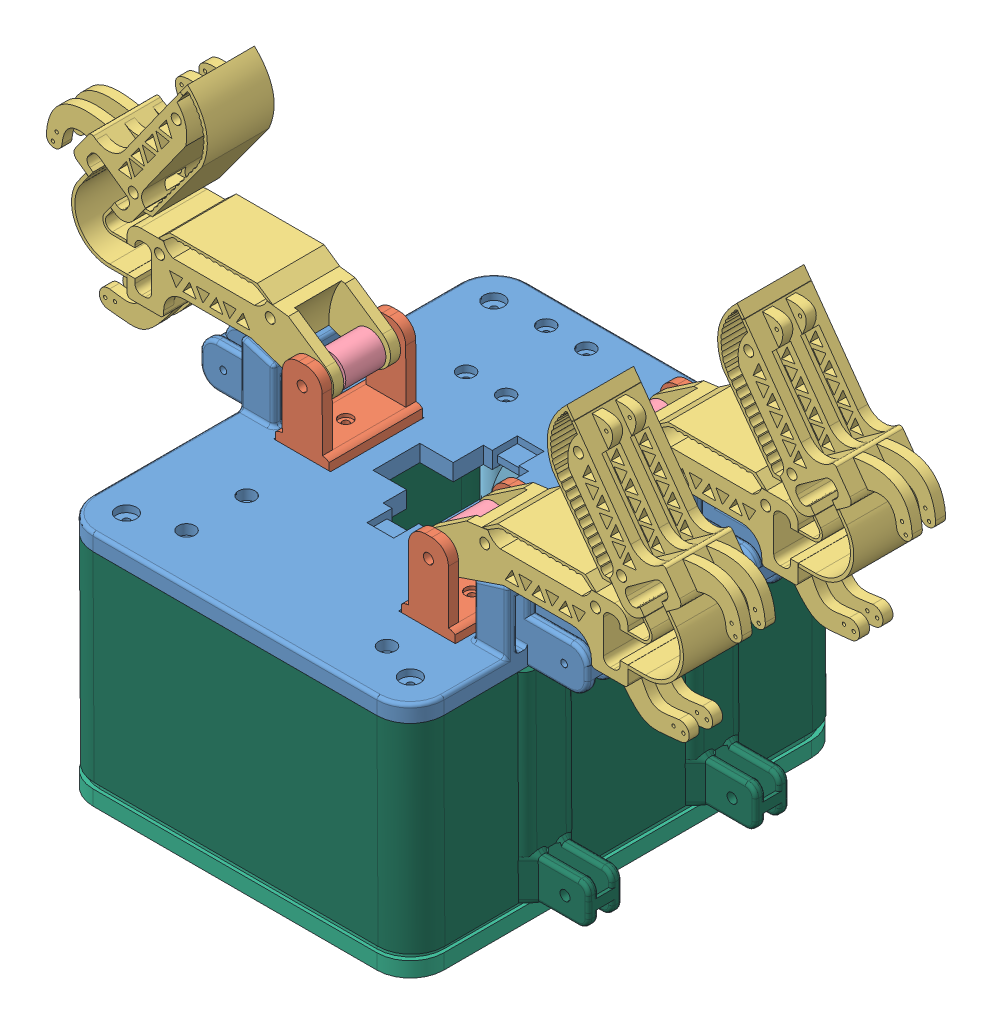
SolidWorks assembly aerial_grasping_robot_hand, configuration 默认. Lengths in mm.
Overall size (234.65 146.24 130.32).
24 component instances, 15 part files, 18 mates.
Components (placement in the parent):
- baseLowerPlate-1: baseLowerPlate [默认] at (-7.9581 -0.8606 143.0257) x (0 0 -1) z (-1 0 0) size (130 26.66 141)
- fingerBase-1: fingerBase [默认] at (40.1258 10.2687 115.4253) x (1 0 0) z (0 -1 0) size (16 28 25)
- fingerBase-2: fingerBase [默认] at (41.0069 10.2687 166.6307) x (1 0 0) z (0 -1 0) size (16 28 25)
- fingerBase-3: fingerBase [默认] at (-22.606 10.2284 140.7805) x (1 0 0) z (0 -0.999996 -0.002874) size (16 28 25)
- finger-1: finger [默认] at (-54.3196 23.2773 150.8484) x (1 0 0) z (0 0.999996 0.002874) size (91.02 20 76.48)
- finger-2: finger [默认] at (63.787 23.3465 105.4079) x (-1 0 0) z (0 1 0) size (91.02 20 76.48)
- finger-3: finger [默认] at (64.6682 23.3465 157.273) x (-1 0 0) z (0 1 0) size (91.02 20 76.48)
- fingerPart-1: fingerPart [默认] at (-26.6322 17.1165 134.7447) x (0.999566 0.02947 0.000085) z (0.02947 -0.999562 -0.002872) size (10 12 10)
- fingerPart-2: fingerPart [默认] at (36.9808 17.1394 161.0193) x (0.999903 -0.013899 0) z (-0.013899 -0.999903 0) size (10 12 10)
- fingerPart-3: fingerPart [默认] at (36.0996 17.1394 109.5602) x (1 0 0) z (0 -1 0) size (10 12 10)
- baseSupport-1: baseSupport [默认] at (46.9674 -68.3606 196) size (6 63.5 6)
- baseSupport-2: baseSupport [默认] at (-38.0326 -68.3606 86) size (6 63.5 6)
- baseSupport-3: baseSupport [默认] at (46.9674 -68.3606 86) size (6 63.5 6)
- baseSupport-4: baseSupport [默认] at (-38.0326 -68.3606 196) size (6 63.5 6)
- baseUpperPlate-2: baseUpperPlate [默认] at (17.4513 -71.8606 145.5161) x (0 0 -1) z (1 0 0) size (130 7.5 105)
- ServoSupport-1: ServoSupport [默认] at (37.5808 -6.8606 130.4759) x (0 0 1) z (1 0 0) size (54.5 36 62.75)
- rotatingWheel1-1: rotatingWheel1 [默认] at (35.4735 -47.2949 146.4878) size (33.9 6 33.86)
- squareShaft-1: squareShaft [默认] at (1.4924 -49.5437 147.5455) x (1 0 0) z (0 0 -1) size (12 34 12)
- spurGear-2: spurGear [默认] at (1.3131 -41.476 148.1427) x (1 0 0) z (0 0 -1) size (38.9 8 38.9)
- dogCollar-2: dogCollar [默认] at (-3.2848 -55.0899 141.79) x (0 0 -1) z (-1 0 0) size (20 6 17.35)
- tendonDrum-1: tendonDrum [默认] at (1.3856 -60.6478 148.1402) x (1 0 0) z (0 0 -1) size (30 6.5 30)
- bearingCap-1: bearingCap [默认] at (1.2959 -22.2286 148.0665) x (0 0 1) z (1 0 0) size (12.2 16.3 12.2)
- rotatingWheel2-2: rotatingWheel2 [默认] at (-1.9165 -17.3158 112.4209) x (0 1 0) z (0 0 -1) size (22 5 48.47)
- baseShell-2: baseShell [默认] at (21.4803 -5.4774 133.3689) x (0 -0.005349 0.999986) z (1 0 0) size (130 60 141)
Mates (geometry in assembly coordinates):
- 重合4: coincident: circle of baseLowerPlate-1; circle of baseSupport-2
- 重合5: coincident: circle of baseLowerPlate-1; circle of baseSupport-3
- 重合6: coincident: circle of baseLowerPlate-1; circle of baseSupport-1
- 重合7: coincident: circle of baseLowerPlate-1; circle of baseSupport-4
- 重合8: coincident: line of baseLowerPlate-1 through (45.0739 -1.8606 101.4253) axis (-1 0 0); line of fingerBase-1 through (28.0996 -1.8606 101.4253) axis (1 0 0)
- 重合9: coincident: line of baseLowerPlate-1 through (28.0739 -1.8606 180.6307) axis (1 0 0); line of fingerBase-2 through (28.9808 -1.8606 180.6307) axis (1 0 0)
- 重合10: coincident: line of baseLowerPlate-1 through (-18.2037 -1.8606 126.7457) axis (-1 0 0); line of fingerBase-3 through (-34.6322 -1.8606 126.7457) axis (1 0 0)
- 同心1: concentric: circle of fingerBase-3; circle of finger-1
- 同心2: concentric: circle of fingerBase-1; circle of finger-2
- 同心3: concentric: circle of fingerBase-2; circle of finger-3
- 同心4: concentric: circle of finger-2; circle of fingerPart-3
- 同心6: concentric: circle of finger-3; circle of fingerPart-2
- 同心7: concentric: circle of finger-1; circle of fingerPart-1
- 重合19: coincident: line of baseLowerPlate-1 through (50.1957 -4.8606 111.5601) axis (-1 0 0); line of ServoSupport-1 through (50.1957 -4.8606 111.5601) axis (-1 0 0)
- 重合20: coincident: line of baseLowerPlate-1 through (50.1957 -4.8606 107.5601) axis (0 0 1); line of ServoSupport-1 through (50.1957 -4.8606 107.7601) axis (0 0 1)
- 重合21: coincident: circle of baseSupport-2; circle of baseUpperPlate-2
- 重合24: coincident: line of baseLowerPlate-1 through (-37.0326 -5.8606 77) axis (1 0 0); line of baseShell-2 through (-38.0304 -5.1705 76.0018) axis (1 0 0)
- 重合28: coincident: line of baseLowerPlate-1 through (45.9674 -5.8606 205) axis (-1 0 0); line of baseShell-2 through (45.9696 -5.8606 205) axis (-1 0 0)
